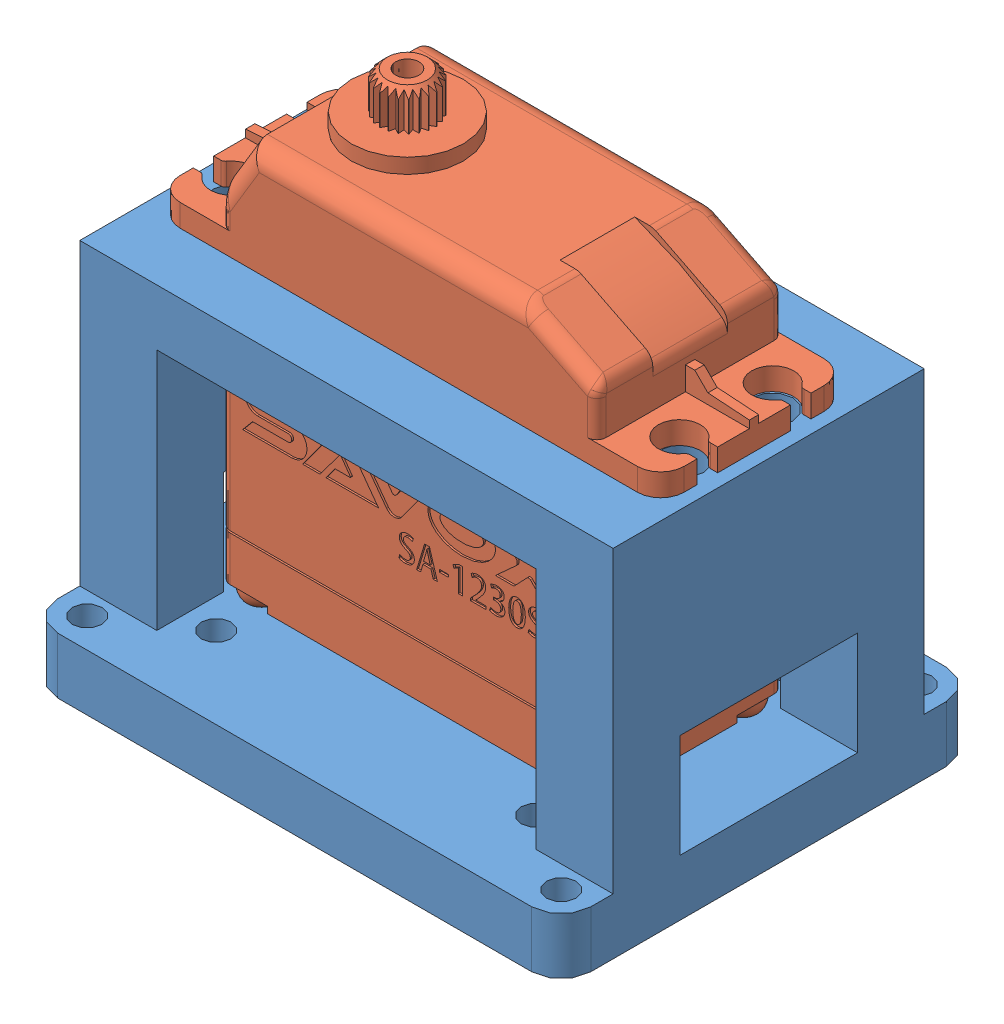
SolidWorks assembly Assem1, configuration Default. Lengths in mm.
Overall size (58.55 55.1 44.45).
2 component instances, 2 part files, 4 mates.
Components (placement in the parent):
- SAVOX_mount-1: SAVOX_mount [Default] at (26.1505 34.4353 38.1923) size (57.15 38.1 44.45)
- Savox SA1230SG-1: Savox SA1230SG [По умолчанию] at (26.3205 53.4853 38.3523) x (1 0 0) z (0 -1 0) size (57.15 20 49.11)
Mates (geometry in assembly coordinates):
- Coincident2: coincident anti-aligned: plane of SAVOX_mount-1 through (46.4705 47.4528 54.861) normal (-1 0 0); plane of Savox SA1230SG-1 through (46.4705 21.3853 28.3523) normal (1 0 0)
- Coincident4: coincident anti-aligned: plane of SAVOX_mount-1 through (54.7255 53.4853 54.0673) normal (0 1 0); plane of Savox SA1230SG-1 through (26.3205 53.4853 38.3523) normal (0 -1 0)
- Coincident5: coincident anti-aligned: plane of SAVOX_mount-1 through (45.6768 22.5291 48.3523) normal (0 0 -1); plane of Savox SA1230SG-1 through (46.4705 21.3853 48.3523) normal (0 0 1)
- Coincident6: coincident anti-aligned: plane of SAVOX_mount-1 through (54.7255 53.4853 54.861) normal (0 1 0); plane of Savox SA1230SG-1 through (26.3205 53.4853 38.3523) normal (0 -1 0)
